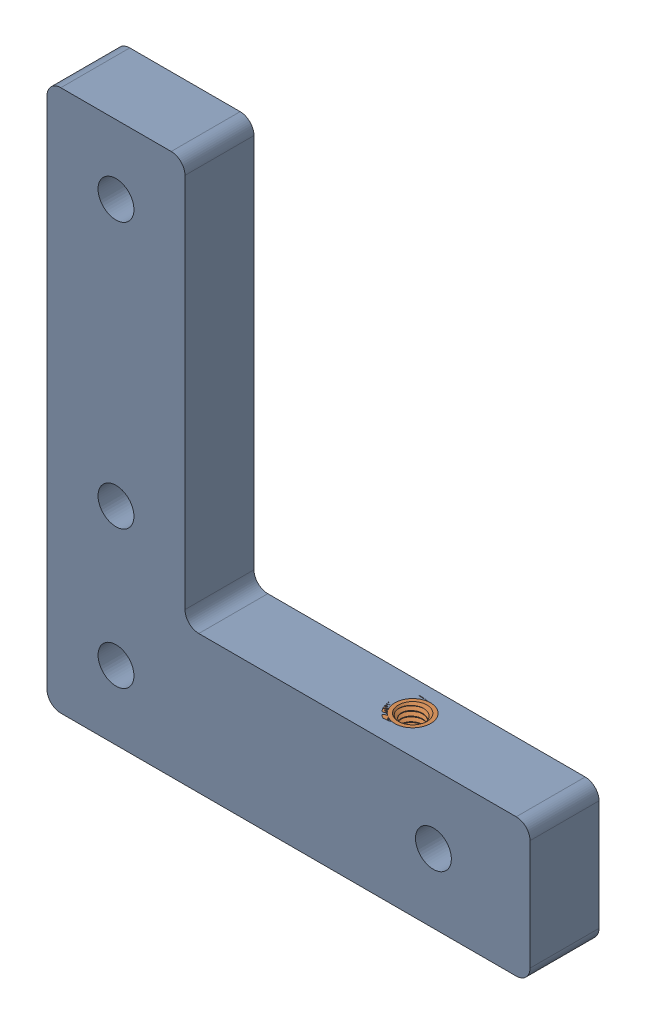
SolidWorks assembly short_motor_corner_plate_spacer_with_insert, configuration Default. Lengths in mm.
Overall size (70 78.5 10).
2 component instances, 2 part files, 0 mates.
Components (placement in the parent):
- motor_corner_bracket_spacer_Left Motor Corner Bracket Spacer-1: motor_corner_bracket_spacer_Left Motor Corner Bracket Spacer [Default] at (-74.7769 0 0) x (0 1 0) z (-1 0 0) size (78.5 10 70)
- m4_heat_set_insert_long_94180A353_94180A353-1: m4_heat_set_insert_long_94180A353_94180A353 [Default] at (-27.2769 20 -5.5) x (0.97178 0 0.235889) z (-0.235889 0 0.97178) size (6.35 8 6.35)
